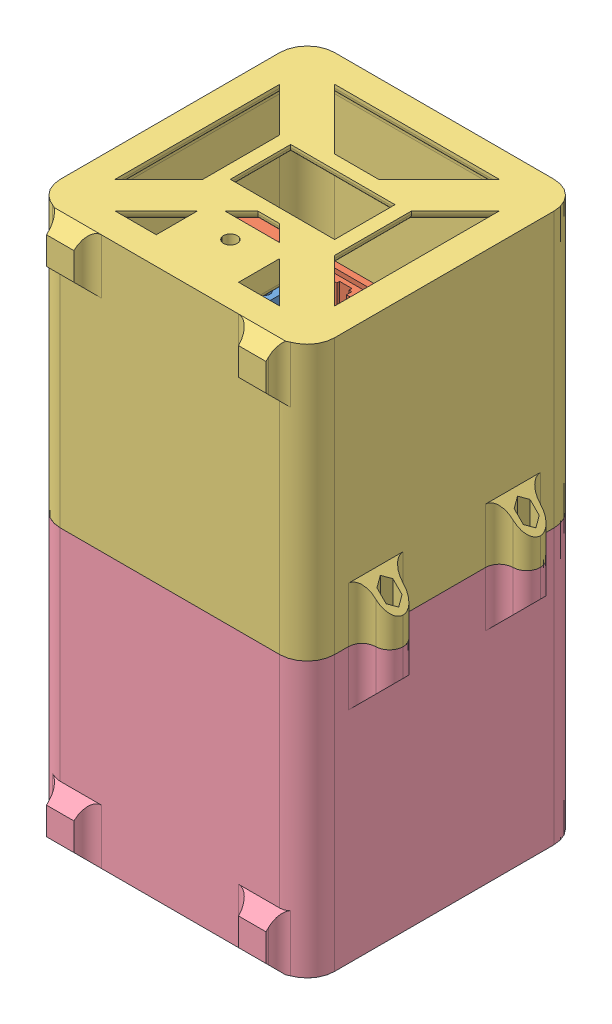
SolidWorks assembly Rittal-Temp, configuration Standard. Lengths in mm.
Overall size (120 200 105).
5 component instances, 5 part files, 12 mates.
Components (placement in the parent):
- Mount-1: Mount [Standard] at (2.5549 -6.4076 54.5) size (66 59.1 23)
- 7030_111-1: 7030_111 [Default] at (2.5549 -22.2076 40.7) x (-1 0 0) z (0 -1 0) size (82.01 29.81 41.1)
- Backside-1: Backside [Standard] at (2.5549 36.5924 39) x (-1 0 0) z (0 -1 0) size (120 105 100)
- Frontside-1: Frontside [Standard] at (2.5549 -163.4076 39) x (1 0 0) z (0 1 0) size (120 105 103)
- Noctua nf-a8-pwm fan 80x80x25 2016-1: Noctua nf-a8-pwm fan 80x80x25 2016 [По умолчанию] at (2.5549 -128.3076 39) x (1 0 0) z (0 -1 0) size (80 80 27.24)
Mates (geometry in assembly coordinates):
- Deckungsgleich1: coincident anti-aligned: plane of Mount-1 through (2.5549 -6.4076 54.5) normal (0 0 -1); plane of 7030_111-1 through (29.4964 1.7924 54.5) normal (0 0 1)
- Deckungsgleich2: coincident aligned: plane of Mount-1 through (2.5549 -30.4076 58.9) normal (0 -1 0); plane of 7030_111-1 through (26.9978 -30.4076 28.8) normal (0 -1 0)
- Breite1: width aligned: plane of Mount-1 through (-30.4451 -6.4076 58.9) normal (-1 0 0); plane of Mount-1 through (35.5549 -6.4076 58.9) normal (1 0 0); plane of 7030_111-1 through (42.9531 -31.2076 29.7651) normal (0.999391 0 -0.034899); plane of 7030_111-1 through (-38.4451 -31.2076 47) normal (-0.999391 0 -0.034899)
- Deckungsgleich3: coincident anti-aligned: plane of Mount-1 through (2.5549 26.5924 58.9) normal (0 1 0); plane of Backside-1 through (2.5549 26.5924 39) normal (0 -1 0)
- Konzentrisch1: concentric aligned: cylinder of Mount-1 through (2.5549 14.1924 67) axis (0 1 0) radius 3; cylinder of Backside-1 through (2.5549 26.5924 67) axis (0 1 0) radius 2.5
- Konzentrisch2: concentric aligned: cylinder of Backside-1 through (-9.9451 33.5924 67) axis (0 -1 0) radius 2.25; cylinder of Mount-1 through (-9.9451 28.6924 67) axis (0 -1 0) radius 2
- Deckungsgleich4: coincident anti-aligned: plane of Backside-1 through (42.5549 -63.4076 -1) normal (0 -1 0); plane of Frontside-1 through (-37.4451 -63.4076 -1) normal (0 1 0)
- Deckungsgleich5: coincident anti-aligned: plane of Frontside-1 through (2.5549 -153.4076 39) normal (0 1 0); plane of Noctua nf-a8-pwm fan 80x80x25 2016-1 through (2.5549 -153.4076 39) normal (0 -1 0)
- Konzentrisch3: concentric anti-aligned: cylinder of Frontside-1 through (38.0549 -153.4076 74.5) axis (0 -1 0) radius 3; cylinder of Noctua nf-a8-pwm fan 80x80x25 2016-1 through (38.0549 -153.3076 74.5) axis (0 1 0) radius 2.2
- Konzentrisch4: concentric anti-aligned: cylinder of Frontside-1 through (-32.9451 -153.4076 3.5) axis (0 -1 0) radius 3; cylinder of Noctua nf-a8-pwm fan 80x80x25 2016-1 through (-32.9451 -153.3076 3.5) axis (0 1 0) radius 2.2
- Deckungsgleich6: coincident aligned: plane of Backside-1 through (2.5549 26.5924 89) normal (0 0 1); plane of Frontside-1 through (2.5549 -153.4076 89) normal (0 0 1)
- Deckungsgleich7: coincident aligned: plane of Backside-1 through (52.5549 26.5924 39) normal (1 0 0); plane of Frontside-1 through (52.5549 -153.4076 39) normal (1 0 0)
